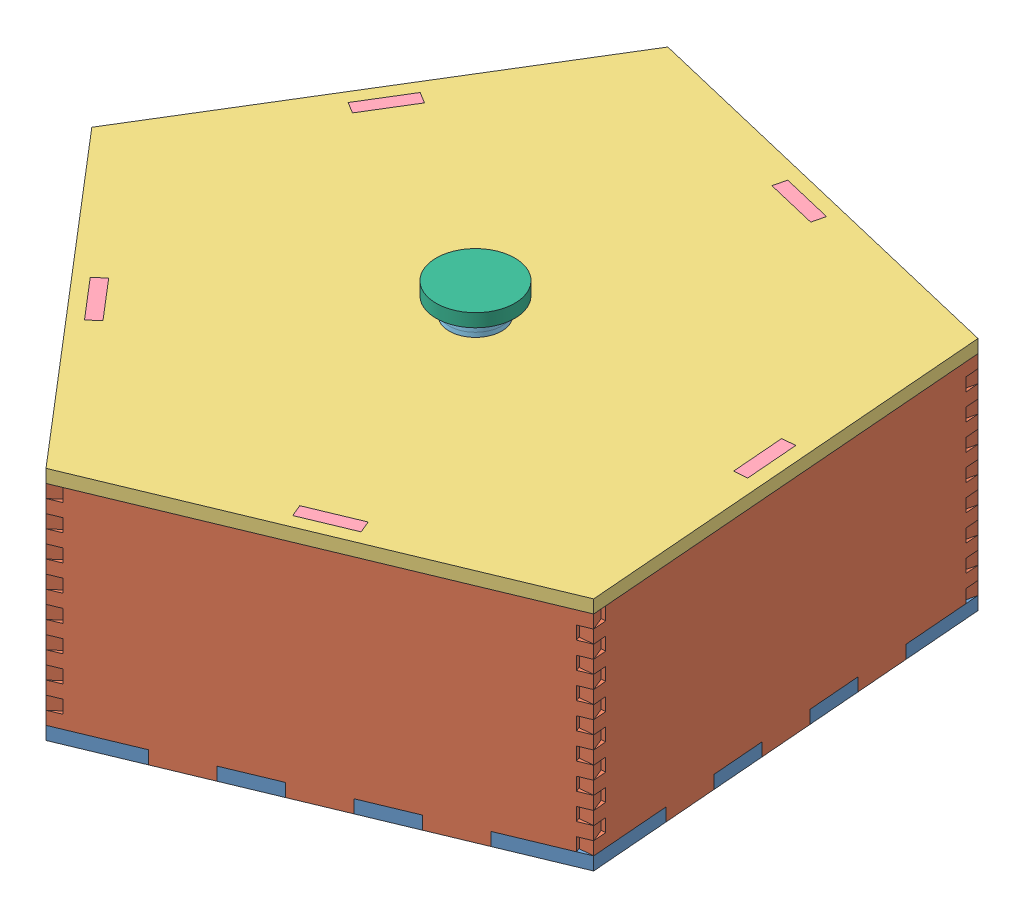
SolidWorks assembly Box assembly, configuration Default. Lengths in mm.
Overall size (328.61 129.15 339.87).
16 component instances, 6 part files, 41 mates.
Components (placement in the parent):
- New Base-1: New Base [Default] at (103.4069 178.6585 332.2248) size (319.79 6.35 327.74)
- Box side new-1: Box side new [Default] at (-72.3107 239.8467 402.7119) x (-0.650338 0 -0.759645) z (0 -1 0) size (203.2 6.35 107.95)
- Box side new-2: Box side new [Default] at (92.1866 239.8467 421.6318) x (-0.923431 0 0.383765) z (0 -1 0) size (203.2 6.35 107.95)
- Box side new-3: Box side new [Default] at (161.0129 239.8467 271.0322) x (0.079627 0 0.996825) z (0 -1 0) size (203.2 6.35 107.95)
- Box side new-4: Box side new [Default] at (39.0527 239.8467 159.0366) x (0.972643 0 0.232306) z (0 -1 0) size (203.2 6.35 107.95)
- Box side new-5: Box side new [Default] at (-105.1492 239.8467 240.4191) x (0.5215 0 -0.853251) z (0 -1 0) size (203.2 6.35 107.95)
- box lid 1-1: box lid 1 [Default] at (190.1024 286.6085 355.5389) x (0.999327 0 -0.036668) z (0.036668 0 0.999327) size (316.77 6.35 328.48)
- box lid insert-1: box lid insert [Default] at (-92.9105 273.9085 359.1214) x (0.650338 0 0.759645) z (0 -1 0) size (101.6 6.35 25.4)
- box lid insert-3: box lid insert [Default] at (-70.0579 273.9085 207.3574) x (-0.5215 0 0.853251) z (0 -1 0) size (101.6 6.35 25.4)
- box lid insert-4: box lid insert [Default] at (152.0567 273.9085 318.4059) x (-0.079627 0 -0.996825) z (0 -1 0) size (101.6 6.35 25.4)
- box lid insert-5: box lid insert [Default] at (81.3402 273.9085 182.1938) x (-0.972643 0 -0.232306) z (0 -1 0) size (101.6 6.35 25.4)
- box lid insert-6: box lid insert [Default] at (44.3639 273.9085 427.7532) x (0.923431 0 -0.383765) z (0 -1 0) size (101.6 6.35 25.4)
- lid handle insert-1: lid handle insert [Default] at (51.3985 282.4089 281.4585) size (25.47 6.35 25.47)
- lid handle insert-2: lid handle insert [Default] at (8.7252 295.1089 268.7542) x (-0.837169 0 -0.546944) z (-0.546944 0 0.837169) size (25.47 6.35 25.47)
- box lid handle-2: box lid handle [Default] at (-6.411 307.8089 256.6923) x (-0.837169 0 -0.546944) z (-0.546944 0 0.837169) size (38.1 6.35 38.1)
- lid handle insert-3: lid handle insert [Default] at (8.7252 301.4589 268.7542) x (-0.837169 0 -0.546944) z (-0.546944 0 0.837169) size (25.47 6.35 25.47)
Mates (geometry in assembly coordinates):
- Coincident1: coincident aligned: plane of New Base-1 through (103.4069 178.6585 332.2248) normal (0 -1 0); plane of Box side new-1 through (-12.3725 178.6585 462.9602) normal (0 -1 0)
- Coincident2: coincident anti-aligned: plane of New Base-1 through (-41.9741 178.6585 438.1473) normal (-0.650338 0 -0.759645); plane of Box side new-1 through (-41.9741 178.6585 438.1473) normal (0.650338 0 0.759645)
- Coincident3: coincident anti-aligned: plane of New Base-1 through (-53.6689 178.6585 414.7227) normal (-0.759645 0 0.650338); plane of Box side new-1 through (-67.4869 239.8467 398.5822) normal (0.759645 0 -0.650338)
- Coincident5: coincident anti-aligned: plane of New Base-1 through (62.4599 178.6585 427.1093) normal (0.383765 0 0.923431); plane of Box side new-2 through (89.7497 239.8467 415.768) normal (-0.383765 0 -0.923431)
- Coincident6: coincident aligned: plane of New Base-1 through (103.4069 178.6585 332.2248) normal (0 -1 0); plane of Box side new-2 through (168.008 178.6585 383.2449) normal (0 -1 0)
- Coincident7: coincident anti-aligned: plane of New Base-1 through (135.2622 178.6585 403.7302) normal (-0.923431 0 0.383765); plane of Box side new-2 through (135.2622 178.6585 403.7302) normal (0.923431 0 -0.383765)
- Coincident8: coincident anti-aligned: plane of New Base-1 through (161.0813 178.6585 351.6353) normal (0.996825 0 -0.079627); plane of Box side new-3 through (154.6831 239.8467 271.5378) normal (-0.996825 0 0.079627)
- Coincident10: coincident aligned: plane of New Base-1 through (103.4069 178.6585 332.2248) normal (0 -1 0); plane of Box side new-3 through (147.935 178.6585 187.0596) normal (0 -1 0)
- Coincident11: coincident anti-aligned: plane of New Base-1 through (157.2986 178.6585 224.533) normal (0.079627 0 0.996825); plane of Box side new-3 through (157.2986 178.6585 224.533) normal (-0.079627 0 -0.996825)
- Coincident12: coincident aligned: plane of New Base-1 through (103.4069 178.6585 332.2248) normal (0 -1 0); plane of Box side new-4 through (-44.8513 178.6585 145.5255) normal (0 -1 0)
- Coincident14: coincident anti-aligned: plane of New Base-1 through (115.732 178.6585 183.8793) normal (0.232306 0 -0.972643); plane of Box side new-4 through (37.5776 239.8467 165.2129) normal (-0.232306 0 0.972643)
- Coincident15: coincident anti-aligned: plane of New Base-1 through (67.7969 178.6585 165.9019) normal (-0.972643 0 -0.232306); plane of Box side new-4 through (67.7969 178.6585 165.9019) normal (0.972643 0 0.232306)
- Coincident16: coincident anti-aligned: plane of New Base-1 through (-57.8272 178.6585 175.1697) normal (-0.853251 0 -0.5215); plane of Box side new-5 through (-99.731 239.8467 243.7307) normal (0.853251 0 0.5215)
- Coincident17: coincident aligned: plane of New Base-1 through (103.4069 178.6585 332.2248) normal (0 -1 0); plane of Box side new-5 through (-143.9268 178.6585 316.0415) normal (0 -1 0)
- Coincident18: coincident anti-aligned: plane of New Base-1 through (-57.8272 178.6585 175.1697) normal (-0.5215 0 0.853251); plane of Box side new-5 through (-63.2453 185.0085 171.8581) normal (0.5215 0 -0.853251)
- Coincident20: coincident anti-aligned: plane of box lid 1-1 through (-86.7061 286.6085 376.1328) normal (0.650338 0 0.759645); plane of box lid insert-1 through (-81.8824 292.9585 372.0031) normal (-0.650338 0 -0.759645)
- Coincident21: coincident anti-aligned: plane of box lid 1-1 through (190.1024 286.6085 355.5389) normal (0 -1 0); plane of box lid insert-1 through (-106.6603 286.6085 343.0606) normal (0 1 0)
- Coincident22: coincident anti-aligned: plane of box lid 1-1 through (-81.8824 286.6085 372.0031) normal (-0.759645 0 0.650338); plane of box lid insert-1 through (-92.9105 273.9085 359.1214) normal (0.759645 0 -0.650338)
- Coincident27: coincident anti-aligned: plane of box lid 1-1 through (190.1024 286.6085 355.5389) normal (0 -1 0); plane of box lid insert-3 through (-59.0321 286.6085 189.3175) normal (0 1 0)
- Coincident28: coincident anti-aligned: plane of box lid 1-1 through (-92.1473 286.6085 243.499) normal (-0.853251 0 -0.5215); plane of box lid insert-3 through (-70.0579 273.9085 207.3574) normal (0.853251 0 0.5215)
- Coincident29: coincident anti-aligned: plane of box lid 1-1 through (-97.5655 286.6085 240.1874) normal (0.5215 0 -0.853251); plane of box lid insert-3 through (-92.1473 292.9585 243.499) normal (-0.5215 0 0.853251)
- Coincident30: coincident aligned: plane of box lid 1-1 through (190.1024 292.9585 355.5389) normal (0 1 0); plane of box lid insert-4 through (160.07 292.9585 338.9757) normal (0 1 0)
- Coincident31: coincident anti-aligned: plane of box lid 1-1 through (148.6839 286.6085 276.1829) normal (0.079627 0 0.996825); plane of box lid insert-4 through (148.6839 292.9585 276.1829) normal (-0.079627 0 -0.996825)
- Coincident32: coincident anti-aligned: plane of box lid 1-1 through (155.0138 286.6085 275.6773) normal (-0.996825 0 0.079627); plane of box lid insert-4 through (158.3865 273.9085 317.9003) normal (0.996825 0 -0.079627)
- Coincident33: coincident aligned: plane of box lid 1-1 through (190.1024 292.9585 355.5389) normal (0 1 0); plane of box lid insert-5 through (103.3794 292.9585 180.929) normal (0 1 0)
- Coincident36: coincident anti-aligned: plane of box lid 1-1 through (41.6166 286.6085 166.1776) normal (0.972643 0 0.232306); plane of box lid insert-5 through (40.1414 292.9585 172.3539) normal (-0.972643 0 -0.232306)
- Coincident38: coincident anti-aligned: plane of box lid 1-1 through (41.6166 286.6085 166.1776) normal (0.972643 0 0.232306); plane of box lid insert-5 through (40.1414 292.9585 172.3539) normal (-0.972643 0 -0.232306)
- Coincident39: coincident anti-aligned: plane of box lid 1-1 through (40.1414 286.6085 172.3539) normal (0.232306 0 -0.972643); plane of box lid insert-5 through (81.3402 273.9085 182.1938) normal (-0.232306 0 0.972643)
- Coincident40: coincident anti-aligned: plane of box lid 1-1 through (83.4781 286.6085 411.4979) normal (-0.923431 0 0.383765); plane of box lid insert-6 through (83.4781 292.9585 411.4979) normal (0.923431 0 -0.383765)
- Coincident41: coincident anti-aligned: plane of box lid 1-1 through (62.4599 286.6085 427.1093) normal (-0.383765 0 -0.923431); plane of box lid insert-6 through (46.8008 273.9085 433.617) normal (0.383765 0 0.923431)
- Coincident42: coincident aligned: plane of box lid 1-1 through (190.1024 292.9585 355.5389) normal (0 1 0); plane of box lid insert-6 through (27.2772 292.9585 441.7308) normal (0 1 0)
- Coincident44: coincident anti-aligned: plane of Box side new-4 through (37.5776 239.8467 165.2129) normal (-0.232306 0 0.972643); plane of box lid insert-5 through (82.8153 273.9085 176.0175) normal (0.232306 0 -0.972643)
- Coincident45: coincident anti-aligned: plane of Box side new-4 through (-44.8513 286.6085 145.5255) normal (0 1 0); plane of box lid 1-1 through (190.1024 286.6085 355.5389) normal (0 -1 0)
- Coincident46: coincident anti-aligned: plane of Box side new-2 through (89.7497 239.8467 415.768) normal (-0.383765 0 -0.923431); plane of box lid insert-6 through (46.8008 273.9085 433.617) normal (0.383765 0 0.923431)
- Coincident47: coincident anti-aligned: plane of lid handle insert-1 through (22.9585 288.7589 298.9663) normal (0 1 0); plane of lid handle insert-2 through (22.9585 288.7589 298.9663) normal (0 -1 0)
- Concentric1: concentric anti-aligned: circle of lid handle insert-1; circle of lid handle insert-2
- Coincident51: coincident anti-aligned: plane of lid handle insert-2 through (22.9585 295.1089 298.9663) normal (0 1 0); plane of lid handle insert-3 through (22.9585 295.1089 298.9663) normal (0 -1 0)
- Coincident52: coincident aligned: circle of lid handle insert-2; circle of lid handle insert-3
- Coincident53: coincident anti-aligned: plane of box lid handle-2 through (22.9585 301.4589 298.9663) normal (0 -1 0); plane of lid handle insert-3 through (22.9585 301.4589 298.9663) normal (0 1 0)
- Concentric2: concentric anti-aligned: circle of lid handle insert-1; circle of box lid handle-2
- Concentric3: concentric anti-aligned: cylinder of box lid 1-1 through (22.9585 286.6085 298.9663) axis (0 1 0) radius 12.7; cylinder of lid handle insert-1 through (22.9585 288.7589 298.9663) axis (0 -1 0) radius 12.7359
